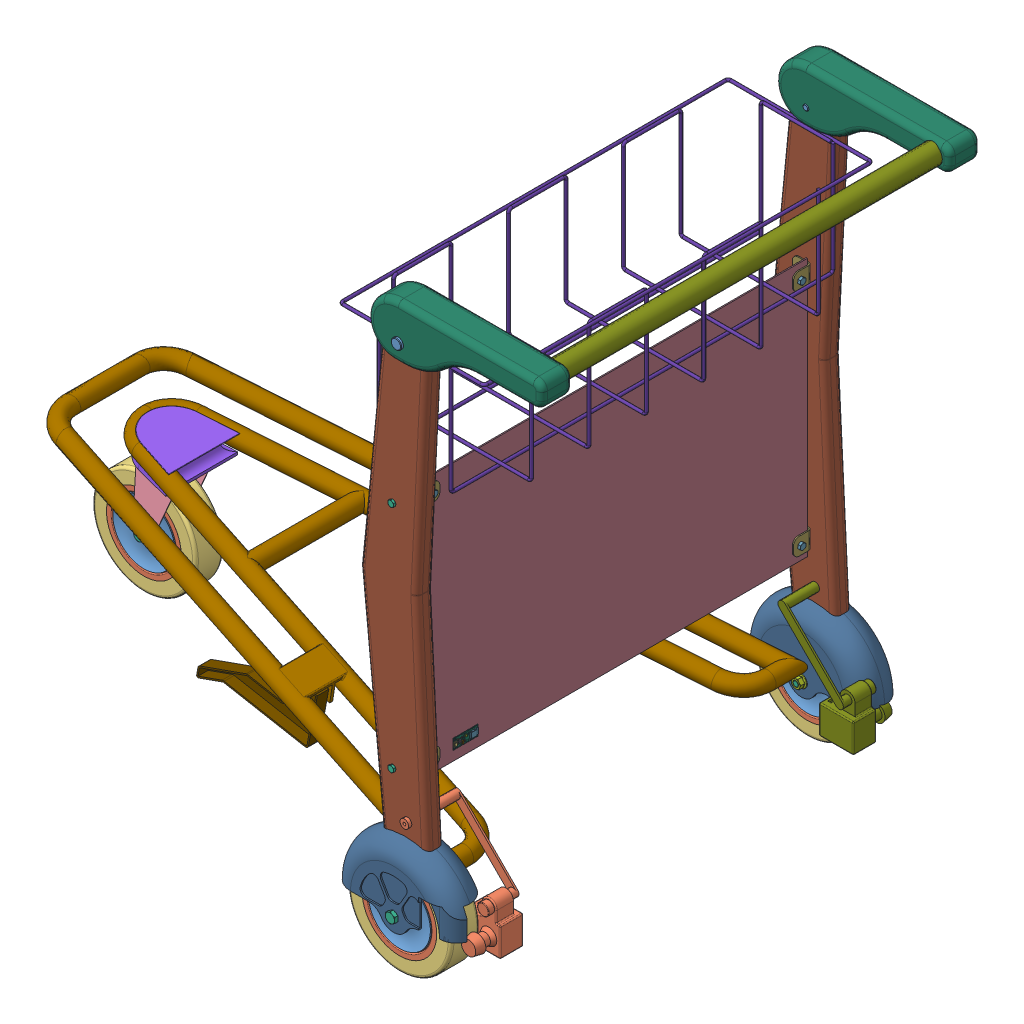
SolidWorks assembly Trolley, configuration Default. Lengths in mm.
Overall size (1159.66 1012.5 792.8).
118 component instances, 34 part files, 6 mates.
Components (placement in the parent):
- Airport Trolley-1: Airport Trolley [Default] at origin size (1159.66 1012.5 792.8)
  - Castor With Bracket-1: Castor With Bracket [Default] at origin size (180 254.25 124.91)
    - Castor Wheel-1: Castor Wheel [Default] at origin size (180 180 79.3)
      - Inside 2-1: Inside 2 [Default] at origin size (110.08 110.08 79.3)
      - Inside 1-1: Inside 1 [Default] at origin size (130 130 50)
      - Rubber Wheel-2: Rubber Wheel [Default] at (0 45 25) x (0 0 1) z (-1 0 0) size (50 180 180)
    - Castor Bracket-1: Castor Bracket [Default] at (-10.2542 104.2118 25) x (0 0 -1) z (-0.060111 -0.998192 0) size (56.48 71.04 113.41)
    - Bracket Top-1: Bracket Top [Default] at (28.7861 104.684 17.6727) x (0.060111 0.998192 0) z (0 0 1) size (15 52 52)
    - hex bolt gradeab_iso-1: hex bolt gradeab_iso [ISO 4014 - M10 x 70 x 26-C] at (0 0 59.6369) x (0 0 -1) z (1 0 0) size (76.4 18.48 16)
    - hex flange nut gradea_iso-2: hex flange nut gradea_iso [Hexagon Flange Nut ISO - 4161 - M10 - N] at (0 0 -13.2369) x (0.923728 0.383049 0) z (0 0 -1) size (21.8 21.8 10)
    - Rubber Top-1: Rubber Top [Default] at (80.9125 134.2079 90) x (-0.989154 0.146881 0) z (0 0 -1) size (106.47 44.76 124.91)
  - Luggage Frame-2: Luggage Frame [Default<As Machined>] at (793.1035 28.4538 320) x (-0.989154 0.146881 0) z (0 0 -1) size (942.05 35.85 636.5)
  - Back Wheel-2: Back Wheel [Default] at (795 0 350) size (220 200 86.4)
    - Castor Wheel-1: Castor Wheel [Default] at origin size (180 180 79.3)
      - Inside 2-1: Inside 2 [Default] at origin size (110.08 110.08 79.3)
      - Inside 1-1: Inside 1 [Default] at origin size (130 130 50)
      - Rubber Wheel-2: Rubber Wheel [Default] at (0 45 25) x (0 0 1) z (-1 0 0) size (50 180 180)
    - Wheel Casing-1: Wheel Casing [Default] at (0 0 -10) size (220 135 70)
    - hex bolt gradeab_iso-1: hex bolt gradeab_iso [ISO 4014 - M10 x 80 x 26-C] at (0 0 66.4) x (0 0 -1) z (1 0 0) size (86.4 18.48 16)
    - hex flange nut gradea_iso-1: hex flange nut gradea_iso [Hexagon Flange Nut ISO - 4161 - M10 - N] at (0 0 -20) x (0.923728 0.383049 0) z (0 0 -1) size (21.8 21.8 10)
  - Back Wheel-3: Back Wheel [Default] at (795 0 -310) x (-1 0 0) z (0 0 -1) size (220 200 86.4)
    - Castor Wheel-1: Castor Wheel [Default] at origin size (180 180 79.3)
      - Inside 2-1: Inside 2 [Default] at origin size (110.08 110.08 79.3)
      - Inside 1-1: Inside 1 [Default] at origin size (130 130 50)
      - Rubber Wheel-2: Rubber Wheel [Default] at (0 45 25) x (0 0 1) z (-1 0 0) size (50 180 180)
    - Wheel Casing-1: Wheel Casing [Default] at (0 0 -10) size (220 135 70)
    - hex bolt gradeab_iso-1: hex bolt gradeab_iso [ISO 4014 - M10 x 80 x 26-C] at (0 0 66.4) x (0 0 -1) z (1 0 0) size (86.4 18.48 16)
    - hex flange nut gradea_iso-1: hex flange nut gradea_iso [Hexagon Flange Nut ISO - 4161 - M10 - N] at (0 0 -20) x (0.923728 0.383049 0) z (0 0 -1) size (21.8 21.8 10)
  - Support-1: Support [Right] at (835 80 -320) x (-1 0 0) z (0 0 -1) size (119.95 779.01 31.28)
  - Support-3: Support [Left] at (835 80 390) x (-1 0 0) z (0 0 -1) size (119.95 779.01 31.28)
  - 'L' Bracket-1: 'L' Bracket [Default] at (791.3545 602.9093 -320) x (1 0 0) z (0 -1 0) size (32.07 32.07 30)
  - 'L' Bracket-2: 'L' Bracket [Default] at (791.3545 202.9093 -320) x (1 0 0) z (0 -1 0) size (32.07 32.07 30)
  - 'L' Bracket-3: 'L' Bracket [Default] at (791.3545 602.9093 360) x (1 0 0) z (0 1 0) size (32.07 32.07 30)
  - 'L' Bracket-4: 'L' Bracket [Default] at (791.3545 202.9093 360) x (1 0 0) z (0 1 0) size (32.07 32.07 30)
  - Advert Board-2: Advert Board [Default] at (789.4275 402.9093 20) x (0 0 -1) z (1 0 0) size (668 450 2)
  - hex bolt gradeab_iso-7: hex bolt gradeab_iso [ISO 4014 - M6 x 40 x 18-N] at (773.8545 602.9093 394) x (0 0 -1) z (1 0 0) size (44 11.55 10)
  - hex bolt gradeab_iso-8: hex bolt gradeab_iso [ISO 4014 - M6 x 40 x 18-N] at (773.8545 202.9093 394) x (0 0 -1) z (1 0 0) size (44 11.55 10)
  - hex bolt gradeab_iso-9: hex bolt gradeab_iso [ISO 4014 - M6 x 40 x 18-N] at (773.8545 202.9093 -354) x (0 0 1) z (-1 0 0) size (44 11.55 10)
  - hex bolt gradeab_iso-10: hex bolt gradeab_iso [ISO 4014 - M6 x 40 x 18-N] at (773.8545 602.9093 -354) x (0 0 1) z (-1 0 0) size (44 11.55 10)
  - hex flange nut gradea_iso-2: hex flange nut gradea_iso [Hexagon Flange Nut ISO - 4161 - M6 - N] at (773.8545 602.9093 352) x (0.923728 0.383049 0) z (0 0 -1) size (14.2 14.2 6)
  - hex flange nut gradea_iso-3: hex flange nut gradea_iso [Hexagon Flange Nut ISO - 4161 - M6 - N] at (773.8545 202.9093 352) x (0.923728 0.383049 0) z (0 0 -1) size (14.2 14.2 6)
  - hex flange nut gradea_iso-4: hex flange nut gradea_iso [Hexagon Flange Nut ISO - 4161 - M6 - N] at (773.8545 202.9093 -312) size (14.2 14.2 6)
  - hex flange nut gradea_iso-5: hex flange nut gradea_iso [Hexagon Flange Nut ISO - 4161 - M6 - N] at (773.8545 602.9093 -312) size (14.2 14.2 6)
  - hex screw gradec_iso-1: hex screw gradec_iso [ISO 4018 - M6 x 12-NN] at (797.8025 602.9093 -300.427) x (-1 0 0) z (0 0.924225 0.381849) size (16.38 11.55 10)
  - hex screw gradec_iso-2: hex screw gradec_iso [ISO 4018 - M6 x 12-NN] at (797.8025 602.9093 340.427) x (-1 0 0) z (0 0.924225 0.381849) size (16.38 11.55 10)
  - hex screw gradec_iso-3: hex screw gradec_iso [ISO 4018 - M6 x 12-NN] at (797.8025 202.9093 340.427) x (-1 0 0) z (0 0.924225 0.381849) size (16.38 11.55 10)
  - hex screw gradec_iso-4: hex screw gradec_iso [ISO 4018 - M6 x 12-NN] at (797.8025 202.9093 -300.427) x (-1 0 0) z (0 0.924225 0.381849) size (16.38 11.55 10)
  - hex flange nut gradea_iso-6: hex flange nut gradea_iso [Hexagon Flange Nut ISO - 4161 - M6 - N] at (783.4275 602.9093 340.427) x (0 0 1) z (-1 0 0) size (14.2 14.2 6)
  - hex flange nut gradea_iso-7: hex flange nut gradea_iso [Hexagon Flange Nut ISO - 4161 - M6 - N] at (783.4275 602.9093 -300.427) x (0 0 1) z (-1 0 0) size (14.2 14.2 6)
  - hex flange nut gradea_iso-8: hex flange nut gradea_iso [Hexagon Flange Nut ISO - 4161 - M6 - N] at (783.4275 202.9093 -300.427) x (0 0 1) z (-1 0 0) size (14.2 14.2 6)
  - hex flange nut gradea_iso-9: hex flange nut gradea_iso [Hexagon Flange Nut ISO - 4161 - M6 - N] at (783.4275 202.9093 340.427) x (0 0 1) z (-1 0 0) size (14.2 14.2 6)
  - Handle-1: Handle [Right] at (795.0187 860 -308) x (-1 0 0) z (0 0 -1) size (303.42 93.75 54)
  - Handle-3: Handle [Left] at (795.0187 860 402) x (-1 0 0) z (0 0 -1) size (303.42 93.75 54)
  - Handle Bar-1: Handle Bar [Default] at (1015.0187 900.625 20) size (34 34 744)
  - Basket-1: Basket [Default] at (775 826 20) x (0 0 1) z (-1 0 0) size (680 200 255)
  - Lock-1: Lock [Right] at (472.1076 75.5835 -160) x (-0.983426 0.181312 0) z (0 0 -1) size (193.3 113.17 20)
  - Lock-2: Lock [Left] at (472.1076 75.5835 220) x (-0.983426 0.181312 0) z (0 0 -1) size (193.3 113.17 20)
  - clevis pin headed_iso-1: clevis pin headed_iso [Clevis Pin ISO 2341 - B - 10 x 55 - St] at (795.0187 860 -366) x (0 0 1) z (-1 0 0) size (59 18 18)
  - clevis pin headed_iso-2: clevis pin headed_iso [Clevis Pin ISO 2341 - B - 10 x 55 - St] at (795.0187 860 406) x (0 0 -1) z (1 0 0) size (59 18 18)
  - hex screw gradec_iso-5: hex screw gradec_iso [ISO 4018 - M5 x 12-NC] at (455.5431 68.4689 -166.375) x (0 0 1) z (-1 0 0) size (15.88 9.24 8)
  - hex screw gradec_iso-6: hex screw gradec_iso [ISO 4018 - M5 x 12-NC] at (435.8746 72.0951 -166.375) x (0 0 1) z (-1 0 0) size (15.88 9.24 8)
  - hex screw gradec_iso-7: hex screw gradec_iso [ISO 4018 - M5 x 12-NC] at (455.5431 68.4689 206.375) x (0 0 -1) z (1 0 0) size (15.88 9.24 8)
  - hex screw gradec_iso-8: hex screw gradec_iso [ISO 4018 - M5 x 12-NC] at (435.8746 72.0951 206.375) x (0 0 -1) z (1 0 0) size (15.88 9.24 8)
  - hex flange nut gradea_iso-10: hex flange nut gradea_iso [Hexagon Flange Nut ISO - 4161 - M5 - C] at (435.8746 72.0951 -150) size (11.8 11.8 5)
  - hex flange nut gradea_iso-11: hex flange nut gradea_iso [Hexagon Flange Nut ISO - 4161 - M5 - C] at (455.5431 68.4689 -150) size (11.8 11.8 5)
  - hex flange nut gradea_iso-12: hex flange nut gradea_iso [Hexagon Flange Nut ISO - 4161 - M5 - C] at (435.76 71.4065 190) x (0.923728 0.383049 0) z (0 0 -1) size (11.8 11.8 5)
  - hex flange nut gradea_iso-13: hex flange nut gradea_iso [Hexagon Flange Nut ISO - 4161 - M5 - C] at (455.5431 68.4689 190) x (0.923728 0.383049 0) z (0 0 -1) size (11.8 11.8 5)
- Dynamo-1: Dynamo [Default] at (898.1471 -10.4741 347.5) x (0 -1 0) z (-1 0 0) size (176.49 93 126.49)
- Nano33BLE.step-1: Nano33BLE.step [Default] at (791.4275 194.915 303.2733) x (0 0 -1) z (1 0 0) size (43.8 17.78 3.58)
  - NANO33BLE_V2.0 v1.step-1: NANO33BLE_V2.0 v1.step [Default] at origin size (43.8 17.78 3.58)
    - 3DComponents.step-1: 3DComponents.step [Default] at origin size (43.76 12.41 2.95)
      - zx62-ab-5pa_31_ v1.step-1: zx62-ab-5pa_31_ v1.step [Default] x (-1 0 0) z (0 1 0) size (5.6 2.95 8.8)
        - 6850961.step-1: 6850961.step [Default] at origin size (5.6 2.95 8.8)
          - ZX62-AB-5PA (1).step-1: ZX62-AB-5PA (1).step [Default] at (-4.98 1.125 5.465) size (5.6 2.95 8.8)
      - IoT_Reser Button v1.step-1: IoT_Reser Button v1.step [Default] x (0 -1 0) z (-1 0 0) size (5.2 2.15 3)
        - User Library-arduino_nano_reset core.step-1: User Library-arduino_nano_reset core.step [Default] at (-8.89 0.805 -11.09) size (5.2 2.15 2.8)
        - User Library-arduino_nano_reset shell.step-1: User Library-arduino_nano_reset shell.step [Default] at (-8.89 2.455 -11.09) x (0 0 1) z (-1 0 0) size (3 1.65 4)
      - RC0402FR-071KL.step-1: RC0402FR-071KL.step [Default] at origin size (35.89 12.12 0.71)
        - RC0402FR-071KL RC0402N_YAG v1.step-1: RC0402FR-071KL RC0402N_YAG v1.step [Default] at (4.8 3.0875 0.805) size (1.07 0.51 0.71)
        - RC0402FR-071KL RC0402N_YAG v1.step-2: RC0402FR-071KL RC0402N_YAG v1.step [Default] at (6.25 4.4075 0.805) x (0 -1 0) z (0 0 1) size (1.07 0.51 0.71)
        - RC0402FR-071KL RC0402N_YAG v1.step-3: RC0402FR-071KL RC0402N_YAG v1.step [Default] at (9.8875 5.5375 0.805) size (1.07 0.51 0.71)
        - RC0402FR-071KL RC0402N_YAG v1.step-4: RC0402FR-071KL RC0402N_YAG v1.step [Default] at (11.27 12.5 0.805) size (1.07 0.51 0.71)
        - RC0402FR-071KL RC0402N_YAG v1.step-5: RC0402FR-071KL RC0402N_YAG v1.step [Default] at (5.4 14.7 0.805) size (1.07 0.51 0.71)
        - RC0402FR-071KL RC0402N_YAG v1.step-6: RC0402FR-071KL RC0402N_YAG v1.step [Default] at (12.225 4.225 0.805) x (0 1 0) z (0 0 1) size (1.07 0.51 0.71)
        - RC0402FR-071KL RC0402N_YAG v1.step-7: RC0402FR-071KL RC0402N_YAG v1.step [Default] at (13.1875 4.2375 0.805) x (0 1 0) z (0 0 1) size (1.07 0.51 0.71)
        - RC0402FR-071KL RC0402N_YAG v1.step-8: RC0402FR-071KL RC0402N_YAG v1.step [Default] at (13.85 10.9 0.805) x (0 -1 0) z (0 0 1) size (1.07 0.51 0.71)
        - RC0402FR-071KL RC0402N_YAG v1.step-9: RC0402FR-071KL RC0402N_YAG v1.step [Default] at (14.8 10.9 0.805) x (0 -1 0) z (0 0 1) size (1.07 0.51 0.71)
        - RC0402FR-071KL RC0402N_YAG v1.step-10: RC0402FR-071KL RC0402N_YAG v1.step [Default] at (15.55 9.275 0.805) size (1.07 0.51 0.71)
        - RC0402FR-071KL RC0402N_YAG v1.step-11: RC0402FR-071KL RC0402N_YAG v1.step [Default] at (16.525 12.75 0.805) x (0 -1 0) z (0 0 1) size (1.07 0.51 0.71)
        - RC0402FR-071KL RC0402N_YAG v1.step-12: RC0402FR-071KL RC0402N_YAG v1.step [Default] at (18 13.675 0.805) size (1.07 0.51 0.71)
        - RC0402FR-071KL RC0402N_YAG v1.step-13: RC0402FR-071KL RC0402N_YAG v1.step [Default] at (18.475 9.775 0.805) size (1.07 0.51 0.71)
        - RC0402FR-071KL RC0402N_YAG v1.step-14: RC0402FR-071KL RC0402N_YAG v1.step [Default] at (18.45 8.6 0.805) size (1.07 0.51 0.71)
        - RC0402FR-071KL RC0402N_YAG v1.step-15: RC0402FR-071KL RC0402N_YAG v1.step [Default] at (21 6.275 0.805) size (1.07 0.51 0.71)
        - RC0402FR-071KL RC0402N_YAG v1.step-16: RC0402FR-071KL RC0402N_YAG v1.step [Default] at (21 5.275 0.805) size (1.07 0.51 0.71)
        - RC0402FR-071KL RC0402N_YAG v1.step-17: RC0402FR-071KL RC0402N_YAG v1.step [Default] at (20.405 3.8 0.805) x (0 -1 0) z (0 0 1) size (1.07 0.51 0.71)
        - RC0402FR-071KL RC0402N_YAG v1.step-18: RC0402FR-071KL RC0402N_YAG v1.step [Default] at (21.395 3.8126 0.805) x (0 -1 0) z (0 0 1) size (1.07 0.51 0.71)
        - RC0402FR-071KL RC0402N_YAG v1.step-19: RC0402FR-071KL RC0402N_YAG v1.step [Default] at (25.075 13.025 0.805) x (0 -1 0) z (0 0 1) size (1.07 0.51 0.71)
        - RC0402FR-071KL RC0402N_YAG v1.step-20: RC0402FR-071KL RC0402N_YAG v1.step [Default] at (26.7 14.2 0.805) size (1.07 0.51 0.71)
        - RC0402FR-071KL RC0402N_YAG v1.step-21: RC0402FR-071KL RC0402N_YAG v1.step [Default] at (39.625 3.32 0.805) size (1.07 0.51 0.71)
        - RC0402FR-071KL RC0402N_YAG v1.step-22: RC0402FR-071KL RC0402N_YAG v1.step [Default] at (37.675 3.32 0.805) size (1.07 0.51 0.71)
        - RC0402FR-071KL RC0402N_YAG v1.step-23: RC0402FR-071KL RC0402N_YAG v1.step [Default] at (35.7 3.3125 0.805) size (1.07 0.51 0.71)
        - RC0402FR-071KL RC0402N_YAG v1.step-24: RC0402FR-071KL RC0402N_YAG v1.step [Default] at (25.4125 3.8125 0.805) x (0 -1 0) z (0 0 1) size (1.07 0.51 0.71)
        - RC0402FR-071KL RC0402N_YAG v1.step-25: RC0402FR-071KL RC0402N_YAG v1.step [Default] at (26.8 10.7 0.805) size (1.07 0.51 0.71)
        - RC0402FR-071KL RC0402N_YAG v1.step-26: RC0402FR-071KL RC0402N_YAG v1.step [Default] at (19.9 14.625 0.805) size (1.07 0.51 0.71)
        - RC0402FR-071KL RC0402N_YAG v1.step-27: RC0402FR-071KL RC0402N_YAG v1.step [Default] at (22.2 14.625 0.805) size (1.07 0.51 0.71)
      - LSM9DS1TR_LGA-24_3X3P5X1_STM v1.step-1: LSM9DS1TR_LGA-24_3X3P5X1_STM v1.step [Default] at (21.5608 12.1142 0.754) size (3.5 3 1.4)
      - IoT_HSMG-C190 LED v1.step-1: IoT_HSMG-C190 LED v1.step [Default] at (1.9 3.1 0.805) x (1 0 0) z (0 -1 0) size (1.6 0.8 0.8)
      - IoT_MPM3610 Step-Down Module v1.step-1: IoT_MPM3610 Step-Down Module v1.step [Default] at (15.675 5.1865 1.605) x (-1 0 0) z (0 1 0) size (3.3 1.65 5.15)
      - IoT_HSMG-C190 LED v1.step-2: IoT_HSMG-C190 LED v1.step [Default] at (1.9 14.7 0.805) x (1 0 0) z (0 -1 0) size (1.6 0.8 0.8)
      - BLM18EG101TN1D v1.step-1: BLM18EG101TN1D v1.step [Default] at (33.0875 2.8875 1.2047) size (1.6 0.65 0.8)
      - C0805C472KDRACTU v1.step-1: C0805C472KDRACTU v1.step [Default] at (14.1625 13 0.8053) x (1 0 0) z (0 -1 0) size (2 1.4 1.25)
      - C0805C472KDRACTU v1.step-2: C0805C472KDRACTU v1.step [Default] at (18.7875 6.0875 0.8053) x (0 -1 0) z (-1 0 0) size (2 1.4 1.25)
      - PMEG6020AELRX v1.step-1: PMEG6020AELRX v1.step [Default] at (7.9 12.95 0.805) x (1 0 0) z (0 -1 0) size (3.5 1.1 1.7)
      - C0805C472KDRACTU v1.step-3: C0805C472KDRACTU v1.step [Default] at (6.8675 6.425 0.8053) x (1 0 0) z (0 -1 0) size (2 1.4 1.25)
      - IoT_PRTR5V0U2X Protection Diode v1.step-1: IoT_PRTR5V0U2X Protection Diode v1.step [Default] at (7.23 9.3 1.455) x (1 0 0) z (0 -1 0) size (3 1.1 2.5)
      - NINA-B306-00B-00--3DModel-STEP-56544 v1.step-1: NINA-B306-00B-00--3DModel-STEP-56544 v1.step [Default] at (35.642 8.89 0.805) x (0 1 0) z (1 0 0) size (10 2.63 15)
    - Board (1).step-1: Board (1).step [Default] at origin size (43.18 17.78 0.81)
- MirrorDynamo-2: MirrorDynamo [Default] at (898.1471 -10.4741 -307.5) x (0 -1 0) z (1 0 0) size (176.49 93 126.49)
Mates (geometry in assembly coordinates):
- Coincident1: coincident: plane of Airport Trolley-1/Advert Board-2 through (791.4275 627.9093 354) normal (1 0 0); plane of Nano33BLE.step-1/NANO33BLE_V2.0 v1.step-1/Board (1).step-1 through (791.4275 203.805 281.6833) normal (-1 0 0)
- Parallel1: parallel: plane of Airport Trolley-1/Advert Board-2 through (791.4275 177.9093 -314) normal (0 -1 0); plane of Nano33BLE.step-1/NANO33BLE_V2.0 v1.step-1/Board (1).step-1 through (791.4275 194.915 303.2733) normal (0 -1 0)
- Tangent1: tangent: cylinder of Airport Trolley-1/Back Wheel-2/Castor Wheel-1/Rubber Wheel-2 through (795 0 400) axis (0 0 1) radius 90; circle of Dynamo-1
- Parallel2: parallel: plane of Dynamo-1 through (918.1471 -35.4741 307.5) normal (0 -1 0); plane of assembly through (0 0 0) normal (0 1 0)
- Parallel3: parallel: plane of Dynamo-1 through (898.1471 -10.4741 347.5) normal (0 0 1); plane of assembly through (0 0 0) normal (0 0 1)
- Distance1: distance = 15 mm: plane of Dynamo-1 through (898.1471 -10.4741 375) normal (0 0 1); plane of Airport Trolley-1/Support-3 through (835 80 390) normal (0 0 1)
